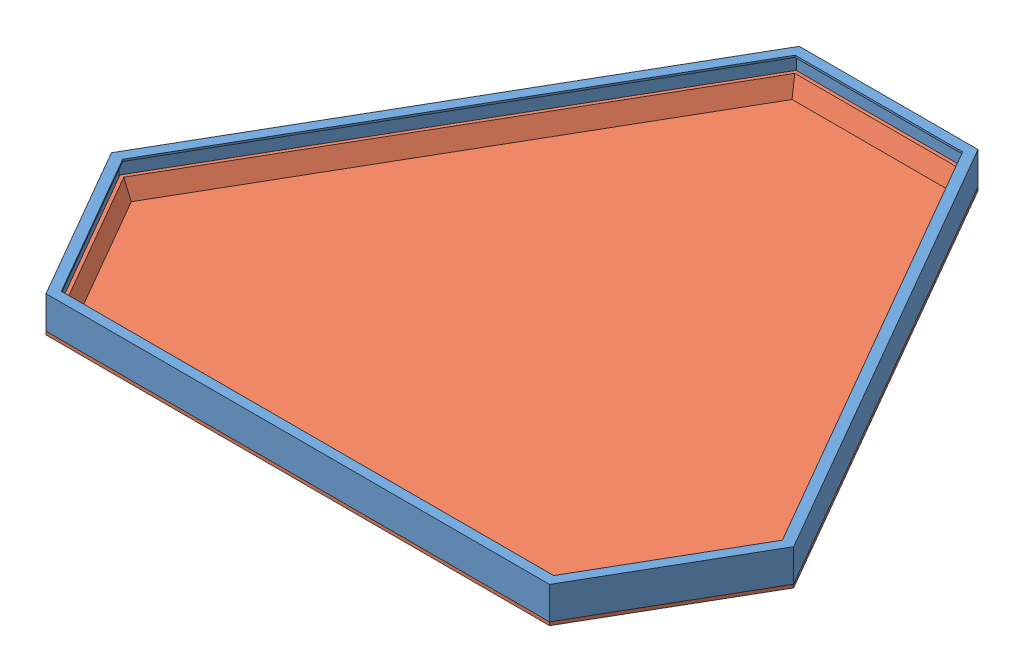
SolidWorks assembly Assem1, configuration Default. Lengths in mm.
Overall size (210 11 181.87).
3 component instances, 3 part files, 8 mates.
Components (placement in the parent):
- Gen3-1: Gen3 [Default] at origin size (210 10 181.87)
- Part2^Assem1-1: Part2^Assem1 [Default] at (0 9.4 0) x (-1 0 0) z (0 -1 0) size (204.69 177.27 4) (hidden, virtual)
- Part4^Assem1-1: Part4^Assem1 [Default] x (-1 0 0) z (0 -1 0) size (210 181.87 6.4) (virtual)
Mates (geometry in assembly coordinates):
- InPlace1: in place: plane of Gen3-1 through (0 9.4 0) normal (0 -1 0); plane of Part2^Assem1-1 through (0 9.4 0) normal (0 -1 0); moOrthogonalPlaneRef_w of Gen3-1 through (0 9.4 0) normal (0 -1 0); plane of Part2^Assem1-1 through (0 9.4 0) normal (0 0 -1); plane of Gen3-1 through (0 9.4 0) normal (0 -1 0); plane of Part2^Assem1-1 through (0 9.4 0) normal (-1 0 0); plane of Gen3-1 through (0 9.4 0) normal (0 -1 0); unknown of Part2^Assem1-1
- Coincident1: coincident aligned: plane of Gen3-1; plane of Part2^Assem1-1
- Coincident2: coincident aligned: moOrthogonalPlaneRef_w of Gen3-1 through (0 9.4 0) normal (0 0 -1); plane of Part2^Assem1-1 through (0 9.4 0) normal (0 0 -1)
- Coincident3: coincident anti-aligned: moOrthogonalPlaneRef_w of Gen3-1 through (0 9.4 0) normal (1 0 0); plane of Part2^Assem1-1 through (0 9.4 0) normal (-1 0 0)
- InPlace2: in place: plane of Gen3-1 through (0 0 0) normal (0 -1 0); plane of Part4^Assem1-1 through (0 0 0) normal (0 -1 0); plane of Gen3-1 through (0 0 0) normal (0 -1 0); plane of Part4^Assem1-1 through (0 0 0) normal (0 0 -1); plane of Gen3-1 through (0 0 0) normal (0 -1 0); plane of Part4^Assem1-1 through (0 0 0) normal (-1 0 0); plane of Gen3-1 through (0 0 0) normal (0 -1 0); unknown of Part4^Assem1-1
- Coincident4: coincident aligned: plane of Gen3-1; plane of Part4^Assem1-1
- Coincident5: coincident aligned: moOrthogonalPlaneRef_w of Gen3-1 through (0 0 0) normal (0 0 -1); plane of Part4^Assem1-1 through (0 0 0) normal (0 0 -1)
- Coincident6: coincident anti-aligned: moOrthogonalPlaneRef_w of Gen3-1 through (0 0 0) normal (1 0 0); plane of Part4^Assem1-1 through (0 0 0) normal (-1 0 0)
